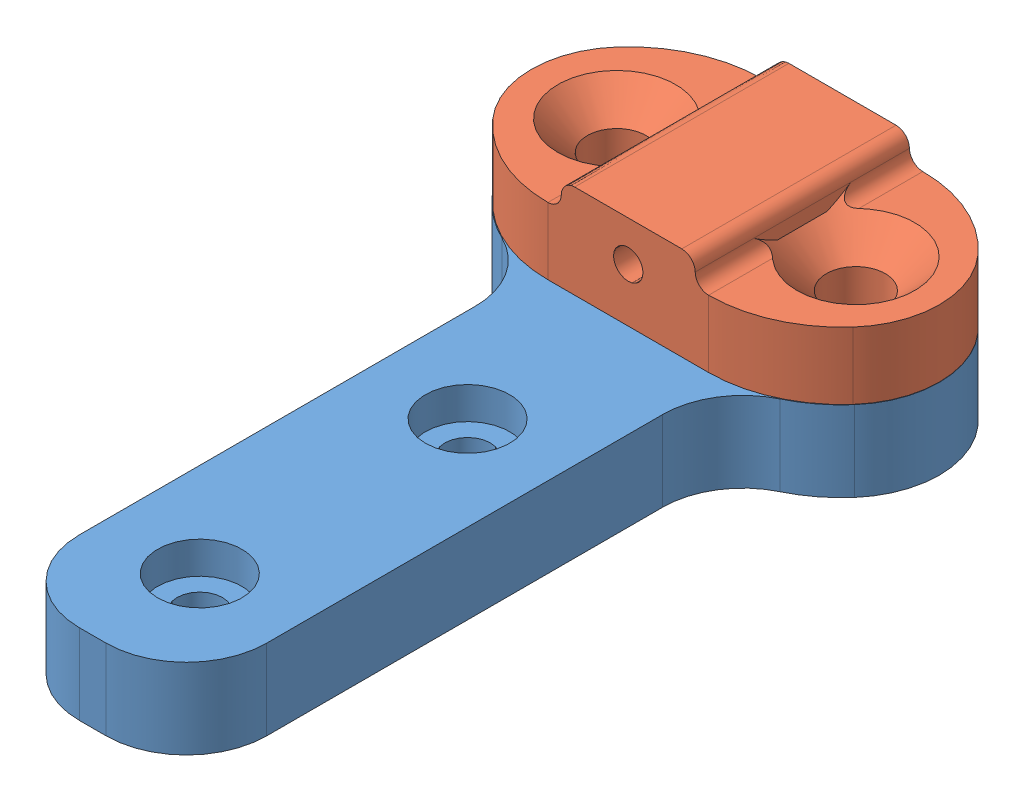
SolidWorks assembly SmarAct Slide Assembly, configuration Default. Lengths in mm.
Overall size (16 6.39 28).
4 component instances, 3 part files, 6 mates.
Components (placement in the parent):
- SmarActSlideMount-1: SmarActSlideMount [Default] at (21.3957 3.7688 -4.2587) size (16 3 28)
- tubeHolder-1: tubeHolder [Default] at (13.3957 6.7688 -10.2587) size (15.24 3.3 8)
- BrassInsert-3: BrassInsert [Default] at (16.8957 3.7688 -14.2587) x (-0.555041 0 -0.831823) z (-0.831823 0 0.555041) size (3.58 3.11 3.58)
- BrassInsert-4: BrassInsert [Default] at (25.8957 3.7688 -14.2587) x (-0.745433 0 -0.666581) z (-0.666581 0 0.745433) size (3.58 3.11 3.58)
Mates (geometry in assembly coordinates):
- Concentric1: concentric aligned: cone of SmarActSlideMount-1 through (25.8957 3.7688 -14.2587) axis (0 1 0); cylinder of tubeHolder-1 through (25.8957 9.2688 -14.2587) axis (0 1 0) radius 1.1
- Coincident1: coincident anti-aligned: plane of SmarActSlideMount-1 through (21.3957 6.7688 -4.2587) normal (0 1 0); plane of tubeHolder-1 through (13.3957 6.7688 -10.2587) normal (0 -1 0)
- Concentric2: concentric aligned: circle of SmarActSlideMount-1; cylinder of BrassInsert-3 through (16.8957 3.7688 -14.2587) axis (0 -1 0) radius 1.79
- Coincident2: coincident aligned: plane of SmarActSlideMount-1 through (21.3957 3.7688 -4.2587) normal (0 -1 0); plane of BrassInsert-3 through (17.8892 3.7688 -12.7697) normal (0 -1 0)
- Concentric3: concentric aligned: cylinder of tubeHolder-1 through (25.8957 9.2688 -14.2587) axis (0 1 0) radius 1.1; cone of BrassInsert-4 through (25.8957 6.5438 -14.2587) axis (0 1 0)
- Coincident3: coincident aligned: plane of SmarActSlideMount-1 through (21.3957 3.7688 -4.2587) normal (0 -1 0); plane of BrassInsert-4 through (27.23 3.7688 -13.0655) normal (0 -1 0)
